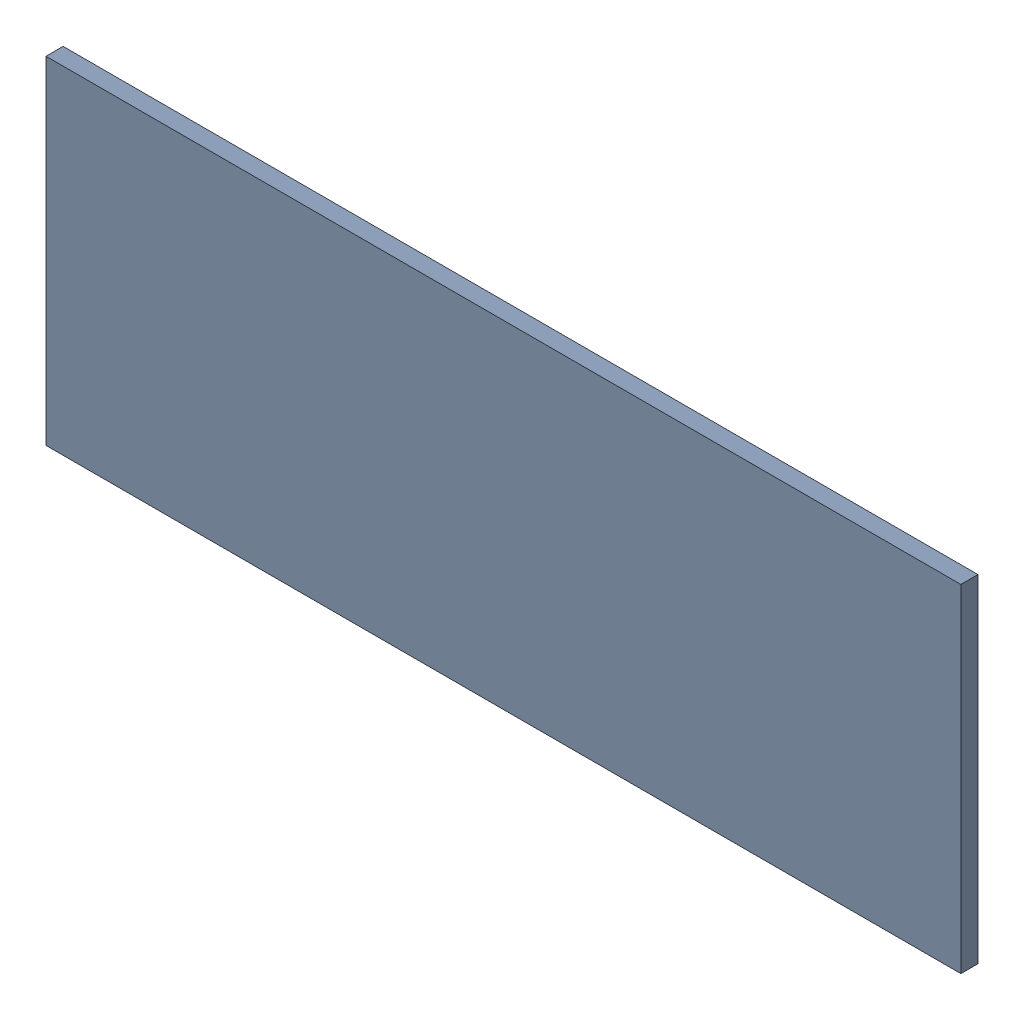
SolidWorks assembly Pad RAK4600-26(29.2mm,17.5mm) on Top Layer, configuration Predeterminado. Lengths in mm.
Overall size (1.9 0.7 0.04).
2 component instances, 1 part files, 0 mates.
Components (placement in the parent):
- Pad RAK4600-26(29.2mm,17.5mm) on Top Layer-1-1: Pad RAK4600-26(29.2mm,17.5mm) on Top Layer-1 [Predeterminado] at (-68.317 -44.187 -0.0457) size (1.9 0.7 0.04)
  - Pad RAK4600-26(29.2mm,17.5mm) on Top Layer-Part-1-1: Pad RAK4600-26(29.2mm,17.5mm) on Top Layer-Part-1 [Predeterminado] at origin size (1.9 0.7 0.04)
